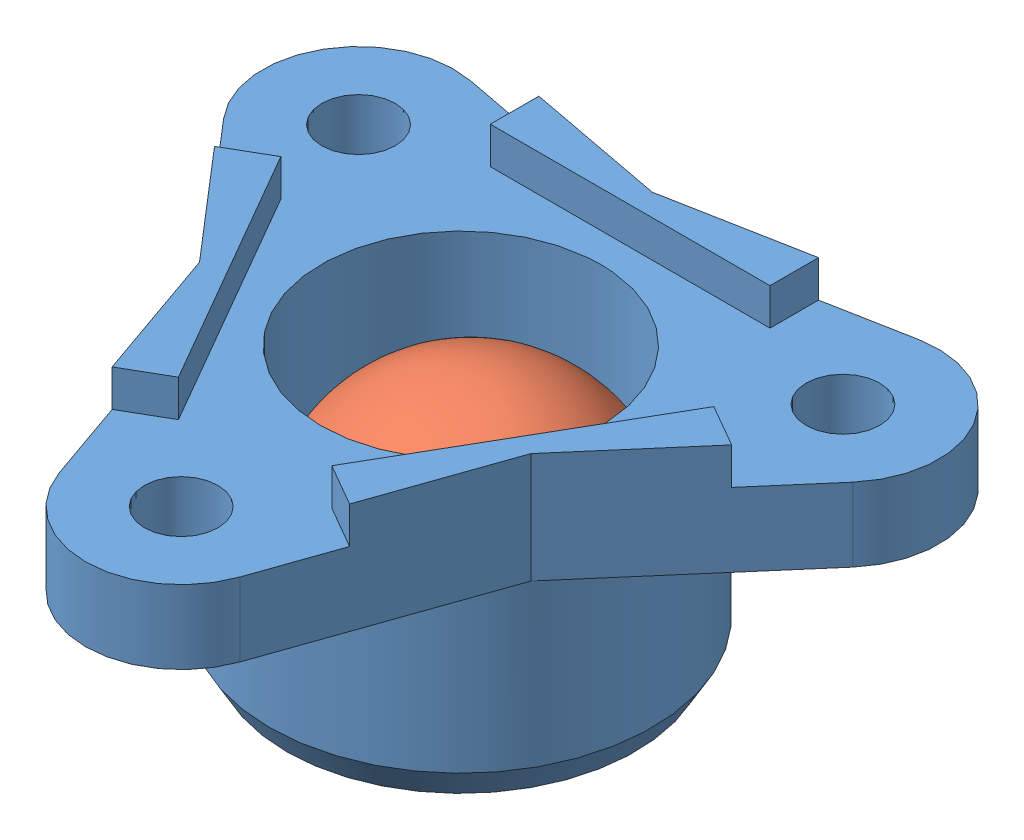
SolidWorks assembly CastorAss, configuration Default. Lengths in mm.
Overall size (22.95 11.75 20.75).
2 component instances, 2 part files, 0 mates.
Components (placement in the parent):
- casterWheel_bottom_V2-2: casterWheel_bottom_V2 [Default] x (1 0 0) z (0 0 -1) size (22.95 10.25 20.75)
- casterWheel-1: casterWheel [Default] at (0.5512 -5.5 0.2177) size (10 10 10)
